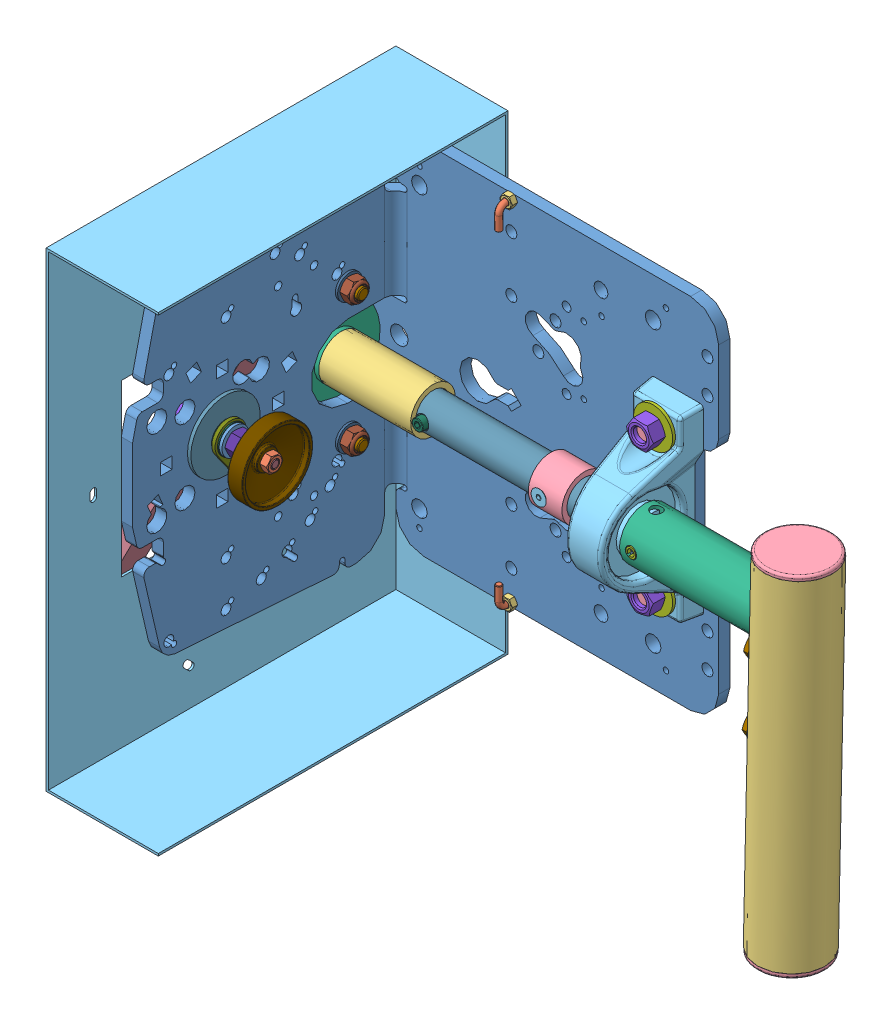
SolidWorks assembly TETE_MANUELLE, configuration Défaut. Lengths in mm.
Overall size (511.4 545.99 392.52).
74 component instances, 41 part files, 26 mates.
Components (placement in the parent):
- 5225PLATINE_023Equipee+-1: 5225PLATINE_023Equipee+ [Défaut] at (-15.1669 -3.7082 0) size (331.9 321 245)
  - 5225 platine_023-1: 5225 platine_023 [Défaut] at (-3.0928 0.9249 0) size (326 320 245)
  - 5248 crochet_006-1: 5248 crochet_006 [Défaut] at (-30.0928 156.4249 0) size (6 21.85 23.8)
  - 5248 crochet_006-2: 5248 crochet_006 [Défaut] at (-30.0928 -154.5751 0) x (-1 0 0) z (0 0 1) size (6 21.85 23.8)
  - eh_6-1: eh_6 [Défaut] at (-30.0928 156.4249 9.8) size (11.55 10 5.2)
  - eh_6-2: eh_6 [Défaut] at (-30.0928 -154.5751 9.8) size (11.55 10 5.2)
  - vis_tf2e_001-1: vis_tf2e_001 [Défaut] at (117.9072 -62.5751 0) x (0 -1 0) z (0 0 -1) size (24 24 40)
  - vis_tf2e_001-2: vis_tf2e_001 [Défaut] at (117.9072 64.4249 0) x (0 -1 0) z (0 0 -1) size (24 24 40)
  - roul_010-1: roul_010 [Défaut] at (117.9038 1.0159 10) x (0 1 0) z (0 0 1) size (163 47 84)
  - roul_009-1: roul_009 [Défaut] at (-143.0928 1.0159 53) x (0 1 0) z (-1 0 0) size (147 78 38)
  - rond_l14-1: rond_l14 [Défaut] at (117.9072 64.4249 29) size (35 35 2.5)
  - rond_l14-3: rond_l14 [Défaut] at (117.9072 -62.5751 29) x (0.661441 0.749997 0) z (0 0 1) size (35 35 2.5)
  - eh_14-1: eh_14 [Défaut] at (117.9072 -62.5751 31.5) x (0.978485 0.206318 0) z (0 0 1) size (24.25 21 12.8)
  - eh_14-2: eh_14 [Défaut] at (117.9072 64.4249 31.5) x (0.998903 -0.046834 0) z (0 0 1) size (24.25 21 12.8)
  - vh_10_40-1: vh_10_40 [Défaut] at (-159.0928 59.4249 53) x (0 0 1) z (-1 0 0) size (18.48 16 46.4)
  - vh_10_40-2: vh_10_40 [Défaut] at (-159.0928 -57.5751 53) x (0 0 1) z (-1 0 0) size (18.48 16 46.4)
  - rond_m_10-1: rond_m_10 [Défaut] at (-157.0928 59.4249 53) x (0 -0.924225 -0.381849) z (-1 0 0) size (22 22 2)
  - rond_m_10-2: rond_m_10 [Défaut] at (-157.0928 -57.5751 53) x (0 0 1) z (-1 0 0) size (22 22 2)
  - rond_m_10-3: rond_m_10 [Défaut] at (-131.0928 -57.5751 53) x (0 0 1) z (-1 0 0) size (22 22 2)
  - rond_m_10-4: rond_m_10 [Défaut] at (-131.0928 59.4249 53) x (0 0 1) z (-1 0 0) size (22 22 2)
  - ehfr_10-1: ehfr_10 [Défaut] at (-131.0928 59.4249 53) x (0 -0.113383 -0.993551) z (1 0 0) size (19.63 17 10)
  - ehfr_10-2: ehfr_10 [Défaut] at (-131.0928 -57.5751 53) x (0 -0.113383 -0.993551) z (1 0 0) size (19.63 17 10)
  - 5309 douille_028-1: 5309 douille_028 [Défaut] at (-143.0928 0.9249 165) x (0 -1 0) z (0 0 1) size (60 9.5 60)
- AXE_LISSE-1: AXE_LISSE [Défaut] at (-202.1597 -63.9004 103.0577) x (0 -0.691429 0.722444) z (-1 0 0) size (421.85 126.92 464)
  - ARBRE_016-1: ARBRE_016 [Défaut] at (-7.4729 11.4763 0) size (413.03 70 398)
    - 4775-1: 4775 [Défaut] at (-71.012 -1.8682 0) size (413.03 70 15)
    - 4774-1: 4774 [Défaut] at (-71.012 -1.8682 -288) x (0.707107 0.707107 0) z (-0.707107 0.707107 0) size (29.9 398 29.9)
    - vchc_6_10-1: vchc_6_10 [Défaut] at (-61.8196 7.3242 -135) x (0.5 -0.5 -0.707107) z (0.707107 0.707107 0) size (10 10 16)
  - 3738 butee-1: 3738 butee [Défaut] at (-3.4849 9.608 0.4) x (0 -1 0) z (0 0 1) size (30 17 14.2)
  - 3738 butee-2: 3738 butee [Défaut] at (-20.4849 9.608 0.4) x (0 -1 0) z (0 0 1) size (30 17 14.2)
  - 3739-1: 3739 [Défaut] at (-7.1041 9.8383 7.5) size (18 60 1.5)
  - 3739-2: 3739 [Défaut] at (-7.1041 9.8383 -9) size (18 60 1.5)
  - rond_m_5-1: rond_m_5 [Défaut] at (-7.1041 26.8383 9) size (12 12 1)
  - rond_m_5-2: rond_m_5 [Défaut] at (-7.1041 26.8383 -10) size (12 12 1)
  - rond_m_5-3: rond_m_5 [Défaut] at (-7.1041 -7.1617 -10) size (12 12 1)
  - rond_m_5-4: rond_m_5 [Défaut] at (-7.1041 -7.1617 9) size (12 12 1)
  - vchc_5_25-1: vchc_5_25 [Défaut] at (-7.1041 -7.1617 10) size (8.5 8.5 30)
  - vchc_5_25-2: vchc_5_25 [Défaut] at (-7.1041 26.8383 10) size (8.5 8.5 30)
  - ehfr_5-1: ehfr_5 [Défaut] at (-7.1041 26.8383 -10) x (-1 0 0) z (0 0 -1) size (9.93 8 6.8)
  - ehfr_5-2: ehfr_5 [Défaut] at (-7.1041 -7.1617 -10) x (-1 0 0) z (0 0 -1) size (9.93 8 6.8)
  - 3929-1: 3929 [Défaut] at (-78.4849 9.608 -89) x (0 0 1) z (-0.812823 0.58251 0) size (82 40 40)
  - 3748-1: 3748 [Défaut] at (-78.4849 9.608 -250) x (0.707107 -0.707107 0) z (0 0 1) size (40 40 30)
  - vfhc_6_15-1: vfhc_6_15 [Défaut] at (-63.8266 24.2664 -245) x (0.5 -0.5 -0.707107) z (0.707107 0.707107 0) size (13.44 13.44 16)
  - 4152-1: 4152 [Défaut] at (-78.4849 9.608 -449) x (0.707107 0.707107 0) z (-0.707107 0.707107 0) size (45 130 130)
  - goup-elast-10-45-2: goup-elast-10-45 [Défaut] at (-78.4522 9.6408 -329) x (0.461048 -0.461048 -0.758201) z (-0.707107 -0.707107 0) size (10 9.83 45)
- MANETON-1: MANETON [Défaut] at (-172.2622 -2.4939 164.304) x (0 0.384015 -0.923327) z (0 -0.923327 -0.384015) size (46.4 30 122.92)
  - 3775-1: 3775 [Défaut] at (-0.7538 0.5025 0) size (30 20 117)
  - 3823-1: 3823 [Défaut] at (4.7462 -17.4975 80.8131) x (0.876657 0 -0.481117) z (0 1 0) size (24 24 10)
  - ehfr_10-1: ehfr_10 [Défaut] at (14.2462 0.5025 -16) x (0 0 -1) z (1 0 0) size (19.63 17 10)
  - vh_10_40-1: vh_10_40 [Défaut] at (-15.7538 0.5025 -16) x (0 0 1) z (-1 0 0) size (18.48 16 46.4)
- GALET+VIS-1: GALET+VIS [Défaut] at (-191.7597 -75.8285 128.4682) x (0 0.658571 0.752519) z (-1 0 0) size (30 30 46.4)
  - roul_015-1: roul_015 [Défaut] at (0.672 0.1301 0) size (30 30 15)
  - vh_10_40 zg 12-9-1: vh_10_40 zg 12-9 [Défaut] at (0.672 0.1301 15) size (18.48 16 46.4)
- rond_m_10-1: rond_m_10 [Défaut] at (220.8403 -100.1689 55.1382) x (0 -0.739651 -0.672991) z (1 0 0) size (22 22 2)
- rond_m_10-2: rond_m_10 [Défaut] at (220.8403 -40.1833 53.8224) x (0 -0.739651 -0.672991) z (1 0 0) size (22 22 2)
- vh_10_40-1: vh_10_40 [Défaut] at (220.8403 -40.1833 53.8224) x (0 0 1) z (-1 0 0) size (18.48 16 46.4)
- vh_10_40-2: vh_10_40 [Défaut] at (220.8403 -100.1689 55.1382) x (0 0 1) z (-1 0 0) size (18.48 16 46.4)
- roul_008-1: roul_008 [Défaut] at (-160.7597 -2.7833 165) x (0 -0.735545 -0.677476) z (1 0 0) size (35 35 8)
- 5309 douille_028-1: 5309 douille_028 [Défaut] at (-158.2597 -2.7833 165) x (0 -0.999772 0.02136) z (0 0.02136 0.999772) size (60 9.5 60)
- ARBRE_MANU-1: ARBRE_MANU [Défaut] at (-142.0802 -3.135 165.8455) x (-1 0 0) z (0 -0.923327 -0.384015) size (84 82.28 95.14)
  - 5012-arbre_027-1: 5012-arbre_027 [Défaut] at (40.6795 0.9157 0) size (82 20 20)
  - 5350 rond_081-1: 5350 rond_081 [Défaut] at (6.1795 0.9157 0) x (0 -0.970018 0.243033) z (0 0.243033 0.970018) size (62 3 62)
  - rond_063-1: rond_063 [Défaut] at (3.1746 0.9157 0) x (0 0 1) z (-1 0 0) size (25 25 1.65)
  - 5029-aiguille-1: 5029-aiguille [Défaut] at (1.5287 0.9157 0) x (0 0 1) z (-1 0 0) size (68 28 3)
  - rond_063-2: rond_063 [Défaut] at (-3.1172 0.9157 0) x (0 -0.924225 -0.381849) z (1 0 0) size (25 25 1.65)
  - eh_12-1: eh_12 [Défaut] at (-5.6221 0.9157 0) x (0 0.055422 0.998463) z (-1 0 0) size (20.78 18 10.8)
  - bouton-sologne-1: bouton-sologne [Défaut] at (-23.3205 0.9157 0) x (-1 0 0) z (0 -0.924225 -0.381849) size (20 63 63)
  - rond_027-1: rond_027 [Défaut] at (-5.6221 0.9157 0) x (1 0 0) z (0 -0.051903 0.998652) size (2.5 24 24)
  - eh_8-1: eh_8 [Défaut] at (-34.3205 0.9157 0) x (0 0 1) z (-1 0 0) size (15.01 13 6.8)
- LISSE_MANU-2: LISSE_MANU [Défaut] at (231.5348 -97.142 55.0718) x (0 -0.999759 0.021931) z (0 0.021931 0.999759) size (308 83.19 83.19)
  - 5056 lr60_0215s-1: 5056 lr60_0215s [Défaut] at (-144.4724 21.1055 0) size (300 60 60)
  - bouchon_004-1: bouchon_004 [Défaut] at (155.5276 21.1055 0) x (0 0.593005 -0.805198) z (0 0.805198 0.593005) size (59.5 22.58 59.5)
  - bouchon_004-2: bouchon_004 [Défaut] at (-144.4724 21.1055 0) x (0 0.970623 -0.240606) z (0 -0.240606 -0.970623) size (59.5 22.58 59.5)
- capot tête Sympact CPGE-1: capot tête Sympact CPGE [Défaut] at (-60.2597 207.2167 -2) x (0 -1 0) z (-1 0 0) size (420 312 100)
Mates (geometry in assembly coordinates):
- Coïncidente1: coincident anti-aligned: plane of 5225PLATINE_023Equipee+-1/roul_009-1 through (-154.1597 -2.6923 38) normal (1 0 0); plane of AXE_LISSE-1/3929-1 through (-154.1597 -2.6923 53) normal (-1 0 0)
- Coaxiale2: concentric anti-aligned: cylinder of 5225PLATINE_023Equipee+-1/roul_010-1 through (102.7369 -2.6923 53) axis (1 0 0) radius 15; cylinder of AXE_LISSE-1/ARBRE_016-1/4774-1 through (25.8403 -2.6923 53) axis (-1 0 0) radius 14.95
- Coaxiale20: concentric aligned: cylinder of MANETON-1/3823-1 through (-181.7597 -75.2881 128.8883) axis (-1 0 0) radius 5; cylinder of GALET+VIS-1/vh_10_40 zg 12-9-1 through (-213.1597 -75.2881 128.8883) axis (-1 0 0) radius 5
- Distance1: distance = 0 mm anti-aligned: plane of MANETON-1/3823-1 through (-191.7597 -75.2881 128.8883) normal (-1 0 0); plane of GALET+VIS-1/roul_015-1 through (-191.7597 -75.2881 128.8883) normal (1 0 0)
- Coaxiale35: concentric aligned: cylinder of AXE_LISSE-1/4152-1 through (416.1153 -40.1833 53.8224) axis (-1 0 0) radius 4.4; cylinder of vh_10_40-1 through (214.4403 -40.1833 53.8224) axis (-1 0 0) radius 5
- Coïncidente31: coincident anti-aligned: plane of rond_m_10-2 through (220.8403 -44.0665 50.2892) normal (-1 0 0); plane of vh_10_40-1 through (220.8403 -34.6833 53.8224) normal (1 0 0)
- Coaxiale36: concentric aligned: cylinder of AXE_LISSE-1/4152-1 through (416.1153 -100.1689 55.1382) axis (-1 0 0) radius 4.4; cylinder of vh_10_40-2 through (214.4403 -100.1689 55.1382) axis (-1 0 0) radius 5
- Coïncidente32: coincident anti-aligned: plane of rond_m_10-1 through (220.8403 -104.0521 51.605) normal (-1 0 0); plane of vh_10_40-2 through (220.8403 -94.6689 55.1382) normal (1 0 0)
- Coaxiale40: concentric aligned: cylinder of roul_008-1 through (-152.7597 -2.7833 165) axis (-1 0 0) radius 17.5; cylinder of 5309 douille_028-1 through (-152.7597 -2.7833 165) axis (-1 0 0) radius 17.5
- Distance3: distance = 0 mm anti-aligned: plane of roul_008-1 through (-152.7597 -2.7833 165) normal (1 0 0); plane of 5309 douille_028-1 through (-152.7597 -2.7833 165) normal (-1 0 0)
- Coïncidente36: coincident anti-aligned: plane of 5225PLATINE_023Equipee+-1/5225 platine_023-1 through (-158.2597 -162.7833 20) normal (-1 0 0); plane of 5309 douille_028-1 through (-158.2597 -2.7833 165) normal (1 0 0)
- Coaxiale41: concentric anti-aligned: cylinder of 5225PLATINE_023Equipee+-1/5225 platine_023-1 through (-649.4872 -2.7833 165) axis (1 0 0) radius 29; cylinder of 5309 douille_028-1 through (-151.2597 -2.7833 165) axis (-1 0 0) radius 29
- Coaxiale42: concentric anti-aligned: cylinder of roul_008-1 through (-152.7597 -2.7833 165) axis (-1 0 0) radius 8.5; cylinder of ARBRE_MANU-1/5012-arbre_027-1 through (-157.7597 -2.7833 165) axis (1 0 0) radius 8.5
- Distance4: distance = 0 mm anti-aligned: plane of roul_008-1 through (-160.7597 -2.7833 165) normal (-1 0 0); plane of ARBRE_MANU-1/5012-arbre_027-1 through (-160.7597 -12.0166 161.1599) normal (1 0 0)
- Coaxiale43: concentric aligned: cylinder of MANETON-1/3775-1 through (-181.7597 -2.7833 165) axis (1 0 0) radius 8.5; cylinder of ARBRE_MANU-1/5012-arbre_027-1 through (-157.7597 -2.7833 165) axis (1 0 0) radius 8.5
- Parallèle2: parallel aligned: plane of MANETON-1/3775-1 through (-181.7597 -13.7153 163.161) normal (0 0.384015 -0.923327); plane of ARBRE_MANU-1/5012-arbre_027-1 through (-139.9859 -12.4866 162.5889) normal (0 0.384015 -0.923327)
- Coïncidente39: coincident anti-aligned: plane of MANETON-1/3775-1 through (-161.7597 -2.7833 165) normal (1 0 0); plane of ARBRE_MANU-1/5012-arbre_027-1 through (-161.7597 -11.0009 161.5823) normal (-1 0 0)
- Coaxiale44: concentric aligned: cylinder of rond_m_10-1 through (220.8403 -100.1689 55.1382) axis (-1 0 0) radius 5.25; cylinder of vh_10_40-2 through (214.4403 -100.1689 55.1382) axis (-1 0 0) radius 5
- Coaxiale45: concentric aligned: cylinder of rond_m_10-2 through (220.8403 -40.1833 53.8224) axis (-1 0 0) radius 5.25; cylinder of vh_10_40-1 through (214.4403 -40.1833 53.8224) axis (-1 0 0) radius 5
- Tangent11: tangent anti-aligned: plane of AXE_LISSE-1/ARBRE_016-1/4775-1 through (-209.6597 -126.3206 203.9041) normal (0 -0.722444 -0.691429); cylinder of GALET+VIS-1/roul_015-1 through (-206.7597 -75.2881 128.8883) axis (1 0 0) radius 15
- Coaxiale48: concentric aligned: cylinder of vh_10_40-1 through (214.4403 -40.1833 53.8224) axis (-1 0 0) radius 5; cylinder of LISSE_MANU-2/5056 lr60_0215s-1 through (534.4095 -40.1833 53.8224) axis (-1 0 0) radius 6
- Coaxiale49: concentric aligned: cylinder of vh_10_40-2 through (214.4403 -100.1689 55.1382) axis (-1 0 0) radius 5; cylinder of LISSE_MANU-2/5056 lr60_0215s-1 through (534.4095 -100.1689 55.1382) axis (-1 0 0) radius 6
- Distance6: distance = 3 mm aligned: plane of AXE_LISSE-1/4152-1 through (226.8403 -2.6923 53) normal (-1 0 0); cylinder of LISSE_MANU-2/5056 lr60_0215s-1 through (252.6403 -252.6322 58.4827) axis (0 0.999759 -0.021931) radius 28.8
- Coïncidente40: coincident anti-aligned: plane of 5225PLATINE_023Equipee+-1/5225 platine_023-1 through (-158.2597 -162.7833 20) normal (-1 0 0); plane of capot tête Sympact CPGE-1 through (-158.2597 207.2167 310) normal (1 0 0)
- Distance7: distance = 0 mm anti-aligned: plane of 5225PLATINE_023Equipee+-1/5225 platine_023-1 through (-138.2597 -162.7833 0) normal (0 0 -1); plane of capot tête Sympact CPGE-1 through (-160.2597 207.2167 0) normal (0 0 1)
- Coaxiale50: concentric aligned: circle of 5225PLATINE_023Equipee+-1/5225 platine_023-1; circle of capot tête Sympact CPGE-1
